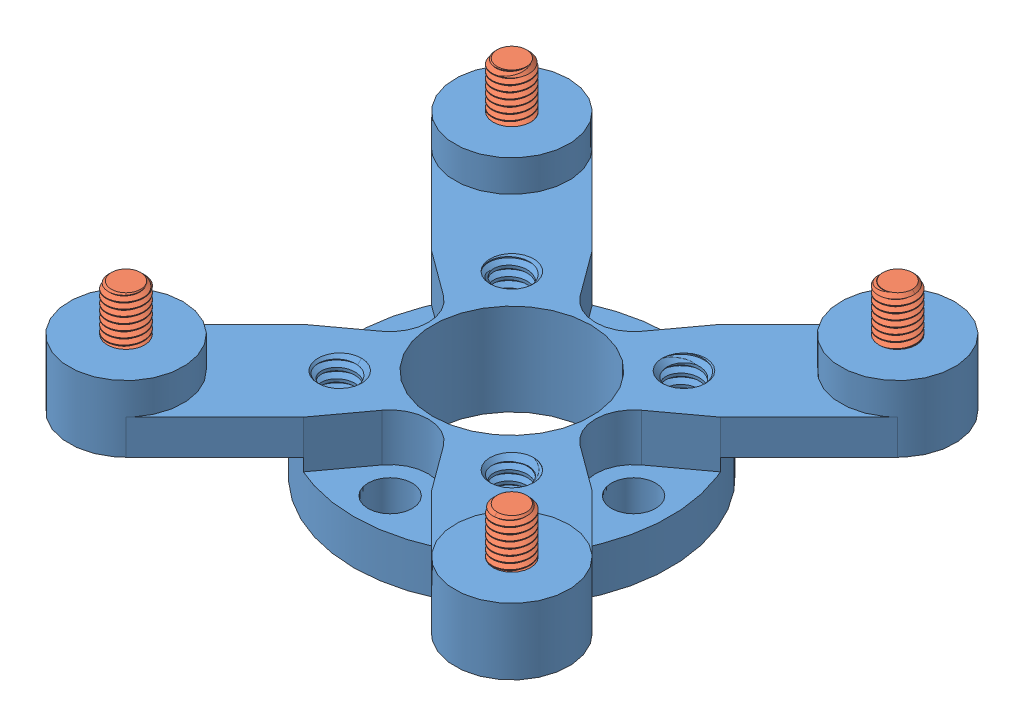
SolidWorks assembly 555152 assembly, configuration Default. Lengths in mm.
Overall size (40.13 13.81 40.13).
5 component instances, 2 part files, 0 mates.
Components (placement in the parent):
- 555152-1: 555152 [Default] at (-46.3202 6.3172 16.8805) size (40.13 10.02 40.13)
- 555152 screw_92005A116-1: 555152 screw_92005A116 [Default] at (-61.8202 19.9372 32.3805) x (1 0 0) z (0 -1 0) size (6 6 8.48)
- 555152 screw_92005A116-2: 555152 screw_92005A116 [Default] at (-30.8202 19.9372 32.3805) x (0 0 -1) z (0 -1 0) size (6 6 8.48)
- 555152 screw_92005A116-3: 555152 screw_92005A116 [Default] at (-30.8202 19.9372 1.3805) x (-1 0 0) z (0 -1 0) size (6 6 8.48)
- 555152 screw_92005A116-4: 555152 screw_92005A116 [Default] at (-61.8202 19.9372 1.3805) x (0 0 1) z (0 -1 0) size (6 6 8.48)
